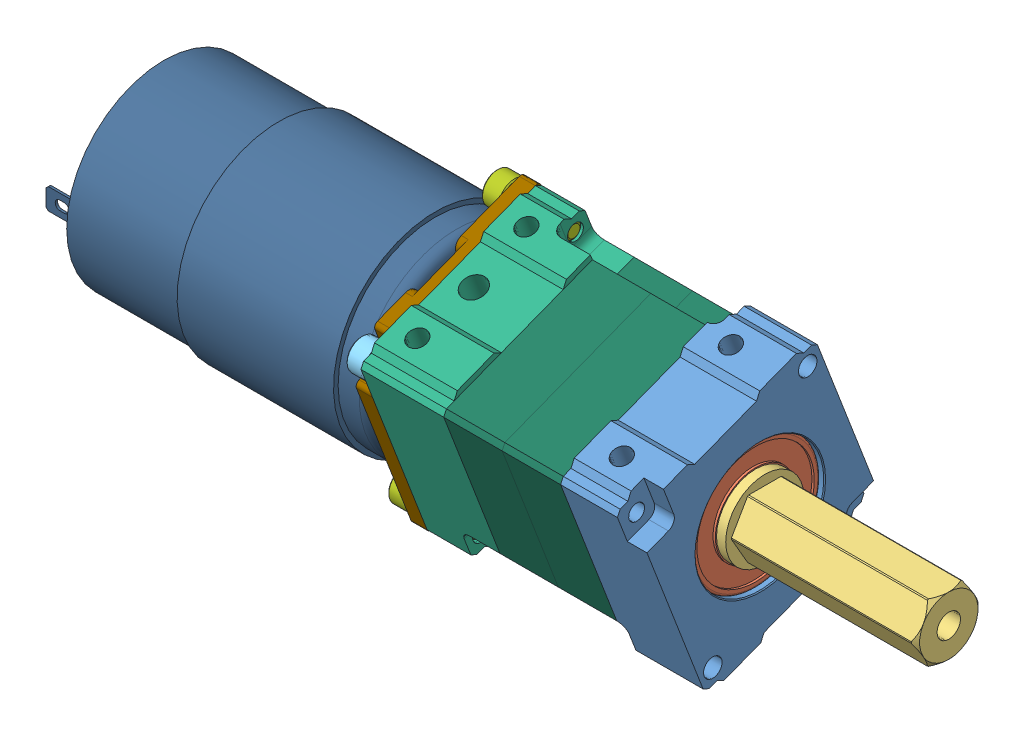
SolidWorks assembly VP, configuration Default. Lengths in mm.
Overall size (179.71 56.57 55.16).
39 component instances, 19 part files, 45 mates.
Components (placement in the parent):
- 217-2625-026 Rev1-1: 217-2625-026 Rev1 [Default] at (-38.8354 -38.0978 -12.7895) x (0 -0.933332 -0.359015) z (-1 0 0) size (44.45 42 18.13)
- 217-2742-001 Rev4-1: 217-2742-001 Rev4 [Default] at (-23.7304 -38.0978 -12.7895) x (1 0 0) z (0 -0.092627 0.995701) size (7 28 28)
- 217-2742-001 Rev4-2: 217-2742-001 Rev4 [Default] at (-32.1352 -38.0978 -12.7895) size (7 28 28)
- 217-2625-003 Rev1_1-1: 217-2625-003 Rev1_1 [Default] at (-24.4828 -38.0978 -12.7895) x (0 -1 0) z (1 0 0) size (17 17 64.12)
- 217-2625-018 Rev1_98541A410-1: 217-2625-018 Rev1_98541A410 [Default] at (-32.6352 -38.0978 -12.7895) x (1 0 0) z (0 -0.017452 0.999848) size (1 19.6 17.4)
- 832-1750-Ring-Gear-Screw_SSA0832-0500ZC-1: 832-1750-Ring-Gear-Screw_SSA0832-0500ZC [Default] at (-75.7354 -48.1483 -35.4056) x (0 0.997447 0.071411) z (0 -0.071411 0.997447) size (6.73 48.51 6.73)
- 832-1750-Ring-Gear-Screw_SSA0832-0500ZC-2: 832-1750-Ring-Gear-Screw_SSA0832-0500ZC [Default] at (-75.7354 -28.0472 9.8266) x (0 0.005929 0.999982) z (0 -0.999982 0.005929) size (6.73 48.51 6.73)
- 217-2625-025 Rev1-1: 217-2625-025 Rev1 [Default] at (-68.2354 -38.0978 -12.7895) x (0 -0.933332 -0.359015) z (-1 0 0) size (44.45 42 18)
- 217-4649-002 Rev1_SSA0832-0500ZC-1: 217-4649-002 Rev1_SSA0832-0500ZC [Default] at (-79.2354 -60.7138 -2.739) x (0 0.33842 -0.940995) z (0 0.940995 0.33842) size (6.73 16.76 6.73)
- 217-4649-002 Rev1_SSA0832-0500ZC-2: 217-4649-002 Rev1_SSA0832-0500ZC [Default] at (-79.2354 -14.8865 -23.1045) x (0 -0.308932 -0.951084) z (0 0.951084 -0.308932) size (6.73 16.76 6.73)
- 217-4649-006 Rev1_SSA0004-008BA-1: 217-4649-006 Rev1_SSA0004-008BA [Default] at (-75.7354 -43.3035 0.7438) x (0 0.5 -0.866025) z (0 -0.866025 -0.5) size (7 14 7)
- 217-4649-006 Rev1_SSA0004-008BA-2: 217-4649-006 Rev1_SSA0004-008BA [Default] at (-75.7354 -32.892 -26.3228) x (0 -1 0) z (0 0 1) size (7 14 7)
- 217-2822-002 Rev4-1: 217-2822-002 Rev4 [Default] at (-77.4854 -38.0978 -12.7895) x (0 -0.933332 -0.359015) z (-1 0 0) size (42 42 5.3)
- 217-4347-000 Rev1-1: 217-4347-000 Rev1 [Default] at (-79.2354 -38.0978 -12.7895) x (-1 0 0) z (0 1 0) size (88 44.3 44.3)
- 217-2820 Rev1_Public-1: 217-2820 Rev1_Public [Default] at (-49.6854 -38.0978 -12.7895) x (0 -0.456494 0.889726) z (-1 0 0) size (39.26 38.9 17.4)
  - 217-2625-100-1: 217-2625-100 [Default] at origin size (39.26 38.9 12.7)
    - 217-2625-008 Rev1-1: 217-2625-008 Rev1 [Default] at origin size (34.7 34.7 4.7)
    - 217-2625-010 Rev1-1: 217-2625-010 Rev1 [Default] at (0 10.193 3.65) x (0.999813 0.019336 0) z (0 0 1) size (4 4 12)
    - 217-2625-010 Rev1-2: 217-2625-010 Rev1 [Default] at (8.691 -5.3258 3.65) size (4 4 12)
    - 217-2625-010 Rev1-3: 217-2625-010 Rev1 [Default] at (-8.691 -5.3258 3.65) size (4 4 12)
    - 217-2625-005 Rev1_Planet_Revolving_Follower01-1: 217-2625-005 Rev1_Planet_Revolving_Follower01 [Default] at (8.691 -5.3258 6.35) x (0.932816 0.360354 0) z (0 0 1) size (16.91 16.92 8)
    - 217-2625-005 Rev1_Planet_Revolving_Follower01-2: 217-2625-005 Rev1_Planet_Revolving_Follower01 [Default] at (-8.691 -5.3258 6.35) x (-0.932788 -0.360426 0) z (0 0 1) size (16.91 16.92 8)
    - 217-2625-005 Rev1_Planet_Revolving_Follower01-3: 217-2625-005 Rev1_Planet_Revolving_Follower01 [Default] at (0 10.193 6.35) x (0.893583 0.448898 0) z (0 0 1) size (16.91 16.92 8)
  - 217-2625-007 Rev1_Public-1: 217-2625-007 Rev1_Public [Default] at (0 0 6.7) x (0.992772 0.120019 0) z (0 0 1) size (14.49 14.49 12.72)
- 217-2816-001 Rev1-1: 217-2816-001 Rev1 [Default] at (-51.3854 -38.0978 -12.7895) x (0 -0.933332 -0.359015) z (1 0 0) size (42 42 14.5)
- 217-4649-001 Rev1-1: 217-4649-001 Rev1 [Default] at (-61.9664 -38.0978 -12.7895) x (0 -1 0) z (1 0 0) size (18 18 13)
- 217-4649-007 Rev1_94105A824-1: 217-4649-007 Rev1_94105A824 [Default] at (-67.4414 -38.0978 -19.301) x (-0.996104 -0.088191 0) z (0 0 -1) size (4.83 4.83 4.9)
- 217-2625-013 Rev2-1: 217-2625-013 Rev2 [Default] at (-66.8164 -38.0978 -12.7895) x (0 0 1) z (-1 0 0) size (8.01 7.94 7.5)
- 217-2816-001 Rev1-2: 217-2816-001 Rev1 [Default] at (-38.6854 -38.0978 -12.7895) x (0 -0.933332 -0.359015) z (1 0 0) size (42 42 14.5)
- 217-2820 Rev1_Public-2: 217-2820 Rev1_Public [Default] at (-36.9854 -38.0978 -12.7895) x (0 -0.383049 0.923728) z (-1 0 0) size (39.26 38.9 17.4)
  - 217-2625-100-1: 217-2625-100 [Default] at origin size (39.26 38.9 12.7)
    - 217-2625-008 Rev1-1: 217-2625-008 Rev1 [Default] at origin size (34.7 34.7 4.7)
    - 217-2625-010 Rev1-1: 217-2625-010 Rev1 [Default] at (0 10.193 3.65) x (0.999813 0.019336 0) z (0 0 1) size (4 4 12)
    - 217-2625-010 Rev1-2: 217-2625-010 Rev1 [Default] at (8.691 -5.3258 3.65) size (4 4 12)
    - 217-2625-010 Rev1-3: 217-2625-010 Rev1 [Default] at (-8.691 -5.3258 3.65) size (4 4 12)
    - 217-2625-005 Rev1_Planet_Revolving_Follower01-1: 217-2625-005 Rev1_Planet_Revolving_Follower01 [Default] at (8.691 -5.3258 6.35) x (0.932816 0.360354 0) z (0 0 1) size (16.91 16.92 8)
    - 217-2625-005 Rev1_Planet_Revolving_Follower01-2: 217-2625-005 Rev1_Planet_Revolving_Follower01 [Default] at (-8.691 -5.3258 6.35) x (-0.932788 -0.360426 0) z (0 0 1) size (16.91 16.92 8)
    - 217-2625-005 Rev1_Planet_Revolving_Follower01-3: 217-2625-005 Rev1_Planet_Revolving_Follower01 [Default] at (0 10.193 6.35) x (0.893583 0.448898 0) z (0 0 1) size (16.91 16.92 8)
  - 217-2625-007 Rev1_Public-1: 217-2625-007 Rev1_Public [Default] at (0 0 6.7) x (0.992772 0.120019 0) z (0 0 1) size (14.49 14.49 12.72)
Mates (geometry in assembly coordinates):
- Concentric1: concentric anti-aligned: cylinder of 217-4649-001 Rev1-1 through (-61.9664 -38.0978 -12.7895) axis (-1 0 0) radius 4.005; cylinder of 217-2625-013 Rev2-1 through (-70.5664 -38.0978 -12.7895) axis (1 0 0) radius 4.005
- Coincident1: coincident aligned: plane of 217-4649-001 Rev1-1 through (-70.5664 -38.0978 -16.7945) normal (-1 0 0); plane of 217-2625-013 Rev2-1 through (-70.5664 -38.0978 -12.7895) normal (-1 0 0)
- Parallel1: parallel aligned: plane of 217-4649-001 Rev1-1 through (-57.5664 -35.0928 -13.7995) normal (0 0 1); plane of 217-2625-013 Rev2-1 through (-70.5664 -35.7129 -13.5395) normal (0 0 1)
- Concentric2: concentric anti-aligned: cylinder of 217-4649-001 Rev1-1 through (-67.4414 -38.0978 -12.7895) axis (0 0 1) radius 2.0193; cylinder of 217-4649-007 Rev1_94105A824-1 through (-67.4414 -38.0978 -17.317) axis (0 0 -1) radius 2.413
- Tangent1: tangent aligned: cylinder of 217-4649-001 Rev1-1 through (-61.9664 -38.0978 -12.7895) axis (-1 0 0) radius 8.4955; plane of 217-4649-007 Rev1_94105A824-1 through (-67.4414 -38.0978 -21.285) normal (0 0 -1)
- Concentric4: concentric aligned: cylinder of 217-4347-000 Rev1-1 through (-79.2354 -38.0978 -12.7895) axis (1 0 0) radius 2.5; cylinder of 217-2625-013 Rev2-1 through (-70.5664 -38.0978 -12.7895) axis (1 0 0) radius 2.5
- Coincident3: coincident anti-aligned: plane of 217-2822-002 Rev4-1 through (-79.2354 -38.0978 -12.7895) normal (-1 0 0); plane of 217-4347-000 Rev1-1 through (-79.2354 -38.0978 -3.8895) normal (1 0 0)
- Concentric5: concentric aligned: cylinder of 217-2822-002 Rev4-1 through (-79.2354 -38.0978 -12.7895) axis (1 0 0) radius 8.65; cylinder of 217-4347-000 Rev1-1 through (-79.2354 -38.0978 -12.7895) axis (1 0 0) radius 8.9
- Concentric6: concentric aligned: cylinder of 217-4649-006 Rev1_SSA0004-008BA-1 through (-85.7354 -43.3035 0.7438) axis (1 0 0) radius 2; cylinder of 217-2822-002 Rev4-1 through (-79.2354 -43.3035 0.7438) axis (1 0 0) radius 2.1
- Coincident4: coincident anti-aligned: plane of 217-4649-006 Rev1_SSA0004-008BA-1 through (-75.7354 -43.3035 0.7438) normal (-1 0 0); plane of 217-2822-002 Rev4-1 through (-75.7354 -38.0978 -12.7895) normal (1 0 0)
- Concentric7: concentric aligned: cylinder of 217-4649-006 Rev1_SSA0004-008BA-2 through (-85.7354 -32.892 -26.3228) axis (1 0 0) radius 2; cylinder of 217-2822-002 Rev4-1 through (-79.2354 -32.892 -26.3228) axis (1 0 0) radius 2.1
- Coincident5: coincident anti-aligned: plane of 217-4649-006 Rev1_SSA0004-008BA-2 through (-75.7354 -32.892 -26.3228) normal (-1 0 0); plane of 217-2822-002 Rev4-1 through (-75.7354 -38.0978 -12.7895) normal (1 0 0)
- Concentric8: concentric anti-aligned: cylinder of 217-4649-002 Rev1_SSA0832-0500ZC-1 through (-66.5354 -60.7138 -2.739) axis (-1 0 0) radius 2.0828; cylinder of 217-2822-002 Rev4-1 through (-79.2354 -60.7138 -2.739) axis (1 0 0) radius 2.18
- Coincident6: coincident anti-aligned: plane of 217-4649-002 Rev1_SSA0832-0500ZC-1 through (-79.2354 -60.7138 -2.739) normal (1 0 0); plane of 217-2822-002 Rev4-1 through (-79.2354 -38.0978 -12.7895) normal (-1 0 0)
- Coincident7: coincident anti-aligned: plane of 217-4649-002 Rev1_SSA0832-0500ZC-2 through (-79.2354 -14.8865 -23.1045) normal (1 0 0); plane of 217-2822-002 Rev4-1 through (-79.2354 -38.0978 -12.7895) normal (-1 0 0)
- Concentric9: concentric anti-aligned: cylinder of 217-4649-002 Rev1_SSA0832-0500ZC-2 through (-66.5354 -14.8865 -23.1045) axis (-1 0 0) radius 2.0828; cylinder of 217-2822-002 Rev4-1 through (-85.7354 -14.8865 -23.1045) axis (1 0 0) radius 2.18
- Concentric10: concentric aligned: cylinder of 217-2625-003 Rev1_1-1 through (44.5516 -38.0978 -12.7895) axis (-1 0 0) radius 7.4955; cylinder of 217-2625-018 Rev1_98541A410-1 through (27.1468 -38.0978 -12.7895) axis (-1 0 0) radius 6.9
- Coincident8: coincident anti-aligned: plane of 217-2625-003 Rev1_1-1 through (26.1468 -38.0978 -20.285) normal (1 0 0); plane of 217-2625-018 Rev1_98541A410-1 through (26.1468 -38.0978 -12.7895) normal (-1 0 0)
- Concentric11: concentric aligned: cylinder of 217-2742-001 Rev4-2 through (27.1468 -38.0978 -12.7895) axis (-1 0 0) radius 7.5; cylinder of 217-2625-003 Rev1_1-1 through (44.5516 -38.0978 -12.7895) axis (-1 0 0) radius 7.4955
- Coincident9: coincident anti-aligned: plane of 217-2742-001 Rev4-2 through (27.1468 -29.3478 -12.7895) normal (-1 0 0); plane of 217-2625-018 Rev1_98541A410-1 through (27.1468 -38.0978 -12.7895) normal (1 0 0)
- Concentric12: concentric aligned: cylinder of 217-2742-001 Rev4-1 through (35.5516 -38.0978 -12.7895) axis (-1 0 0) radius 7.5; cylinder of 217-2625-003 Rev1_1-1 through (44.5516 -38.0978 -12.7895) axis (-1 0 0) radius 7.4955
- Coincident10: coincident anti-aligned: plane of 217-2742-001 Rev4-1 through (42.5516 -30.63 -12.0948) normal (1 0 0); plane of 217-2625-003 Rev1_1-1 through (42.5516 -38.0978 -12.7895) normal (-1 0 0)
- Concentric13: concentric anti-aligned: circle of 217-2625-025 Rev1-1; cylinder of 217-4649-001 Rev1-1 through (-61.9664 -38.0978 -12.7895) axis (-1 0 0) radius 8.4955
- Concentric14: concentric anti-aligned: cylinder of 217-2625-025 Rev1-1 through (-45.0354 -14.8865 -23.1045) axis (1 0 0) radius 1.7272; cylinder of 217-4649-002 Rev1_SSA0832-0500ZC-2 through (-66.5354 -14.8865 -23.1045) axis (-1 0 0) radius 2.0828
- Coincident11: coincident anti-aligned: plane of 217-2625-025 Rev1-1 through (-75.7354 -66.8202 -0.0253) normal (-1 0 0); plane of 217-2822-002 Rev4-1 through (-75.7354 -38.0978 -12.7895) normal (1 0 0)
- Concentric15: concentric aligned: cylinder of 832-1750-Ring-Gear-Screw_SSA0832-0500ZC-2 through (-31.2854 -28.0472 9.8266) axis (-1 0 0) radius 2.0828; cylinder of 217-2625-025 Rev1-1 through (-75.7354 -28.0472 9.8266) axis (-1 0 0) radius 2.2479
- Concentric16: concentric aligned: cylinder of 832-1750-Ring-Gear-Screw_SSA0832-0500ZC-1 through (-31.2854 -48.1483 -35.4056) axis (-1 0 0) radius 2.0828; circle of 217-2625-025 Rev1-1
- Coincident12: coincident anti-aligned: plane of 832-1750-Ring-Gear-Screw_SSA0832-0500ZC-2 through (-75.7354 -28.0472 9.8266) normal (1 0 0); plane of 217-2625-025 Rev1-1 through (-75.7354 -66.8202 -0.0253) normal (-1 0 0)
- Coincident13: coincident anti-aligned: plane of 832-1750-Ring-Gear-Screw_SSA0832-0500ZC-1 through (-75.7354 -48.1483 -35.4056) normal (1 0 0); plane of 217-2625-025 Rev1-1 through (-75.7354 -66.8202 -0.0253) normal (-1 0 0)
- Concentric17: concentric anti-aligned: cylinder of 217-2820 Rev1_Public-1/217-2625-100-1/217-2625-008 Rev1-1 through (-52.0354 -38.0978 -12.7895) axis (1 0 0) radius 17.35; cylinder of 217-2816-001 Rev1-1 through (-45.0344 -38.0978 -12.7895) axis (-1 0 0) radius 19
- Concentric18: concentric aligned: cylinder of 217-2625-026 Rev1-1 through (43.5716 -38.0978 -12.7895) axis (-1 0 0) radius 13.995; cylinder of 217-2742-001 Rev4-1 through (35.5516 -38.0978 -12.7895) axis (-1 0 0) radius 14
- Coincident14: coincident anti-aligned: plane of 217-2625-026 Rev1-1 through (34.1468 -38.0978 -12.7895) normal (-1 0 0); plane of 217-2742-001 Rev4-2 through (34.1468 -25.3478 -12.7895) normal (1 0 0)
- Concentric19: concentric anti-aligned: circle of 217-2625-003 Rev1_1-1; cylinder of 217-2820 Rev1_Public-1/217-2625-100-1/217-2625-008 Rev1-1 through (-52.0354 -38.0978 -12.7895) axis (1 0 0) radius 17.35
- Concentric20: concentric anti-aligned: circle of 217-2625-026 Rev1-1; cylinder of 217-2816-001 Rev1-1 through (-45.0344 -38.0978 -12.7895) axis (-1 0 0) radius 19
- Coincident15: coincident anti-aligned: plane of 217-2820 Rev1_Public-1/217-2625-100-1/217-2625-008 Rev1-1 through (-52.0354 -38.0978 -12.7895) normal (-1 0 0); plane of 217-2816-001 Rev1-1 through (-52.0354 -38.0978 -12.7895) normal (1 0 0)
- Concentric21: concentric anti-aligned: cylinder of 832-1750-Ring-Gear-Screw_SSA0832-0500ZC-1 through (-31.2854 -48.1483 -35.4056) axis (-1 0 0) radius 2.0828; cylinder of 217-2816-001 Rev1-1 through (-45.0354 -48.1483 -35.4056) axis (1 0 0) radius 2.1526
- Concentric22: concentric anti-aligned: circle of 217-2625-025 Rev1-1; circle of 217-2816-001 Rev1-1
- Concentric23: concentric anti-aligned: cylinder of 217-2625-026 Rev1-1 through (39.3076 -48.1483 -35.4056) axis (1 0 0) radius 1.7272; cylinder of 832-1750-Ring-Gear-Screw_SSA0832-0500ZC-1 through (-31.2854 -48.1483 -35.4056) axis (-1 0 0) radius 2.0828
- Coincident16: coincident anti-aligned: plane of 217-2625-025 Rev1-1 through (-57.7354 -25.3336 15.9329) normal (1 0 0); plane of 217-2816-001 Rev1-1 through (-57.7354 -50.1584 -39.9288) normal (-1 0 0)
- Concentric24: concentric anti-aligned: cylinder of 217-2816-001 Rev1-2 through (-32.3344 -38.0978 -12.7895) axis (-1 0 0) radius 19; cylinder of 217-2820 Rev1_Public-2/217-2625-100-1/217-2625-008 Rev1-1 through (-39.3354 -38.0978 -12.7895) axis (1 0 0) radius 17.35
- Coincident18: coincident anti-aligned: plane of 217-2816-001 Rev1-2 through (-39.3354 -38.0978 -12.7895) normal (1 0 0); plane of 217-2820 Rev1_Public-2/217-2625-100-1/217-2625-008 Rev1-1 through (-39.3354 -38.0978 -12.7895) normal (-1 0 0)
- Concentric25: concentric aligned: circle of 217-2816-001 Rev1-1; circle of 217-2816-001 Rev1-2
- Concentric26: concentric anti-aligned: cylinder of 832-1750-Ring-Gear-Screw_SSA0832-0500ZC-2 through (-31.2854 -28.0472 9.8266) axis (-1 0 0) radius 2.0828; cylinder of 217-2816-001 Rev1-2 through (-32.3354 -28.0472 9.8266) axis (1 0 0) radius 2.1526
- Coincident20: coincident anti-aligned: plane of 217-2816-001 Rev1-1 through (-45.0354 -50.1584 -39.9288) normal (1 0 0); plane of 217-2816-001 Rev1-2 through (-45.0354 -50.1584 -39.9288) normal (-1 0 0)
- Coincident21: coincident anti-aligned: plane of 217-2625-026 Rev1-1 through (-32.3354 -38.0978 -12.7895) normal (-1 0 0); plane of 217-2816-001 Rev1-2 through (-32.3354 -50.1584 -39.9288) normal (1 0 0)
